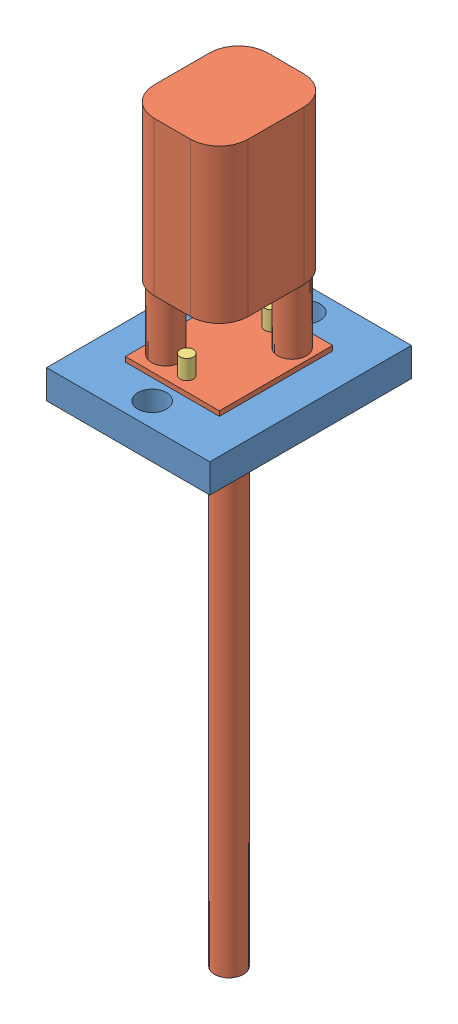
SolidWorks assembly Linear actuator plus assembly, configuration Default. Lengths in mm.
Overall size (17 78.5 23).
4 component instances, 3 part files, 7 mates.
Components (placement in the parent):
- Linear Actuator attachement-1: Linear Actuator attachement [Default] at (8.2903 8.1032 15.183) size (17 3 23)
- Linear actuator-2: Linear actuator [Default] at (8.2903 11.1032 15.183) size (9.8 78.5 11.81)
- 1mm tube-1: 1mm tube [Default] at (8.2903 6.6032 19.583) x (0.99977 0 -0.021452) z (0.021452 0 0.99977) size (1.37 7 1.37)
- 1mm tube-3: 1mm tube [Default] at (8.2903 6.6032 10.783) x (0.528859 0 -0.84871) z (0.84871 0 0.528859) size (1.37 7 1.37)
Mates (geometry in assembly coordinates):
- Concentric1: concentric: circle of Linear Actuator attachement-1; circle of Linear actuator-2
- Parallel1: parallel: line of Linear Actuator attachement-1 through (-0.2097 11.1032 26.683) axis (1 0 0); line of Linear actuator-2 through (3.3903 11.1032 21.083) axis (1 0 0)
- Coincident2: coincident: plane of Linear Actuator attachement-1 through (8.2903 11.1032 15.183) normal (0 1 0); plane of Linear actuator-2 through (8.2903 11.1032 15.183) normal (0 -1 0)
- Concentric2: concentric: circle of Linear actuator-2; circle of 1mm tube-1
- Coincident4: coincident: plane of Linear actuator-2 through (8.2903 11.6032 15.183) normal (0 1 0); plane of 1mm tube-1 through (8.2903 11.6032 19.583) normal (0 -1 0)
- Concentric3: concentric: cylinder of Linear actuator-2 through (8.2903 66.1032 10.783) axis (0 -1 0) radius 0.5; circle of 1mm tube-3
- Coincident5: coincident: plane of Linear actuator-2 through (8.2903 11.6032 15.183) normal (0 1 0); plane of 1mm tube-3 through (8.2903 11.6032 10.783) normal (0 -1 0)
